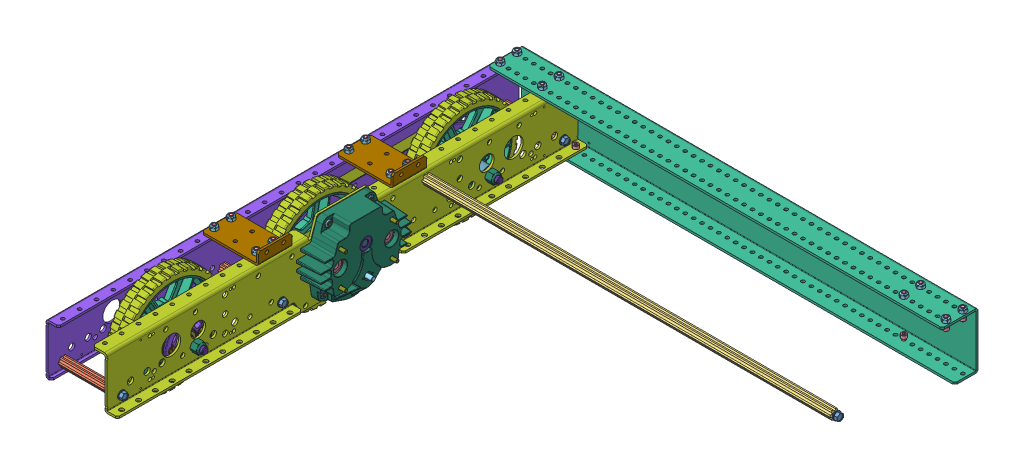
SolidWorks assembly AM14U3 Square Half, configuration Default. Lengths in mm.
Overall size (722.96 215.23 715.14).
150 component instances, 35 part files, 25 mates.
Components (placement in the parent):
- AM14U3 Square Frame Half-1: AM14U3 Square Frame Half [Default] at (326.068 37.2757 -291.2758) size (722.38 116.33 715.14)
  - 0.25-20 x 0.75 in Thread Rolling Screw-1: 0.25-20 x 0.75 in Thread Rolling Screw [FHTS 0.25-20-G-0.75-C] at (-600.075 -67.691 639.064) x (-1 0 0) z (0 0.924225 0.381849) size (24.64 12.19 12.19)
  - 0.25-20 x 0.75 in Thread Rolling Screw-4: 0.25-20 x 0.75 in Thread Rolling Screw [FHTS 0.25-20-G-0.75-C] at (-600.075 -67.691 -27.94) x (-1 0 0) z (0 0.924225 0.381849) size (24.64 12.19 12.19)
  - 0.25-20 x 0.75 in Thread Rolling Screw-5: 0.25-20 x 0.75 in Thread Rolling Screw [FHTS 0.25-20-G-0.75-C] at (-692.15 -67.691 -27.813) size (24.64 12.19 12.19)
  - 0.25-20 x 0.75 in Thread Rolling Screw-7: 0.25-20 x 0.75 in Thread Rolling Screw [FHTS 0.25-20-G-0.75-C] at (-603.25 -15.494 178.562) size (24.64 12.19 12.19)
  - 0.25-20 x 0.75 in Thread Rolling Screw-9: 0.25-20 x 0.75 in Thread Rolling Screw [FHTS 0.25-20-G-0.75-C] at (-692.15 -67.691 638.937) size (24.64 12.19 12.19)
  - 0.25-20 x 0.75 in Thread Rolling Screw-10: 0.25-20 x 0.75 in Thread Rolling Screw [FHTS 0.25-20-G-0.75-C] at (19.05 -15.494 178.562) x (-1 0 0) z (0 0.525103 -0.851039) size (24.64 12.19 12.19)
  - 500 Churro 3.375 in-1: 500 Churro 3.375 in [Default] at (-603.25 -67.691 -27.813) x (0 -0.866025 0.5) z (-1 0 0) size (14.66 12.7 85.72)
  - 500 Churro 3.375 in-2: 500 Churro 3.375 in [Default] at (-603.25 -67.691 638.937) x (0 -0.866025 0.5) z (-1 0 0) size (14.66 12.7 85.72)
  - 500 Churro 24.25 in-1: 500 Churro 24.25 in [Default] at (15.875 -15.494 178.562) x (0 0 -1) z (-1 0 0) size (14.66 12.7 615.95)
  - 10-32 x 0.5 in SHCS Screw-19: 10-32 x 0.5 in SHCS Screw [HX-SHCS 0.19-32x1.375x1-C] at (-679.45 -11.43 -11.938) x (0 1 0) z (0 0 1) size (17.53 7.94 7.94)
  - 10-32 x 0.5 in SHCS Screw-20: 10-32 x 0.5 in SHCS Screw [HX-SHCS 0.19-32x1.375x1-C] at (-679.45 -11.43 -37.338) x (0 1 0) z (0 0 1) size (17.53 7.94 7.94)
  - 10-32 x 0.5 in SHCS Screw-21: 10-32 x 0.5 in SHCS Screw [HX-SHCS 0.19-32x1.375x1-C] at (-615.95 -11.43 -37.338) x (0 1 0) z (0 0 1) size (17.53 7.94 7.94)
  - 10-32 x 0.5 in SHCS Screw-22: 10-32 x 0.5 in SHCS Screw [HX-SHCS 0.19-32x1.375x1-C] at (-615.95 -11.43 -11.938) x (0 1 0) z (0 0 1) size (17.53 7.94 7.94)
  - 10-32 x 0.5 in SHCS Screw-23: 10-32 x 0.5 in SHCS Screw [HX-SHCS 0.19-32x1.375x1-C] at (-590.55 -73.152 -37.338) x (0 -1 0) z (0 0 1) size (17.53 7.94 7.94)
  - 10-32 x 0.5 in SHCS Screw-24: 10-32 x 0.5 in SHCS Screw [HX-SHCS 0.19-32x1.375x1-C] at (-6.35 -11.176 -37.338) x (0 1 0) z (0.222581 0 0.974914) size (17.53 7.94 7.94)
  - 10-32 x 0.5 in SHCS Screw-25: 10-32 x 0.5 in SHCS Screw [HX-SHCS 0.19-32x1.375x1-C] at (-6.35 -11.176 -11.938) x (0 1 0) z (0.81526 0 0.579096) size (17.53 7.94 7.94)
  - 10-32 x 0.5 in SHCS Screw-26: 10-32 x 0.5 in SHCS Screw [HX-SHCS 0.19-32x1.375x1-C] at (-69.85 -11.176 -37.338) x (0 1 0) z (0 0 1) size (17.53 7.94 7.94)
  - 10-32 x 0.5 in SHCS Screw-27: 10-32 x 0.5 in SHCS Screw [HX-SHCS 0.19-32x1.375x1-C] at (-69.85 -11.176 -11.938) x (0 1 0) z (0.111454 0 0.99377) size (17.53 7.94 7.94)
  - 10-32 x 0.5 in SHCS Screw-28: 10-32 x 0.5 in SHCS Screw [HX-SHCS 0.19-32x1.375x1-C] at (-95.25 -73.406 -37.338) x (0 -1 0) z (0.007214 0 0.999974) size (17.53 7.94 7.94)
  - 10-32 Nylock Nut-19: 10-32 Nylock Nut [Default] at (-679.45 0 -11.938) x (1 0 0) z (0 1 0) size (10.18 11.01 7.1)
  - 10-32 Nylock Nut-21: 10-32 Nylock Nut [Default] at (-679.45 0 -37.338) x (1 0 0) z (0 1 0) size (10.18 11.01 7.1)
  - 10-32 Nylock Nut-22: 10-32 Nylock Nut [Default] at (-615.95 0 -11.938) x (1 0 0) z (0 1 0) size (10.18 11.01 7.1)
  - 10-32 Nylock Nut-23: 10-32 Nylock Nut [Default] at (-615.95 0 -37.338) x (1 0 0) z (0 1 0) size (10.18 11.01 7.1)
  - 10-32 Nylock Nut-25: 10-32 Nylock Nut [Default] at (-69.85 0 -11.938) x (1 0 0) z (0 1 0) size (10.18 11.01 7.1)
  - 10-32 Nylock Nut-26: 10-32 Nylock Nut [Default] at (-69.85 0 -37.338) x (1 0 0) z (0 1 0) size (10.18 11.01 7.1)
  - 10-32 Nylock Nut-27: 10-32 Nylock Nut [Default] at (-6.35 0 -11.938) x (1 0 0) z (0 1 0) size (10.18 11.01 7.1)
  - 10-32 Nylock Nut-28: 10-32 Nylock Nut [Default] at (-6.35 0 -37.338) x (1 0 0) z (0 1 0) size (10.18 11.01 7.1)
  - 10-32 Nylock Nut-29: 10-32 Nylock Nut [Default] at (-95.25 -84.582 -37.338) x (1 0 0) z (0 -1 0) size (10.18 11.01 7.1)
  - 10-32 Nylock Nut-30: 10-32 Nylock Nut [Default] at (-590.55 -84.582 -37.338) x (1 0 0) z (0 -1 0) size (10.18 11.01 7.1)
  - 10-32 x 0.5 in SHCS Screw-29: 10-32 x 0.5 in SHCS Screw [HX-SHCS 0.19-32x1.375x1-C] at (-679.45 -11.43 191.262) x (0 1 0) z (0 0 1) size (17.53 7.94 7.94)
  - 10-32 x 0.5 in SHCS Screw-30: 10-32 x 0.5 in SHCS Screw [HX-SHCS 0.19-32x1.375x1-C] at (-679.45 -11.43 216.662) x (0 1 0) z (0 0 1) size (17.53 7.94 7.94)
  - 10-32 x 0.5 in SHCS Screw-31: 10-32 x 0.5 in SHCS Screw [HX-SHCS 0.19-32x1.375x1-C] at (-615.95 -11.43 191.262) x (0 1 0) z (0 0 1) size (17.53 7.94 7.94)
  - 10-32 x 0.5 in SHCS Screw-32: 10-32 x 0.5 in SHCS Screw [HX-SHCS 0.19-32x1.375x1-C] at (-615.95 -11.43 216.662) x (0 1 0) z (0 0 1) size (17.53 7.94 7.94)
  - 10-32 x 0.5 in SHCS Screw-33: 10-32 x 0.5 in SHCS Screw [HX-SHCS 0.19-32x1.375x1-C] at (-615.95 -11.43 394.462) x (0 1 0) z (0 0 1) size (17.53 7.94 7.94)
  - 10-32 x 0.5 in SHCS Screw-34: 10-32 x 0.5 in SHCS Screw [HX-SHCS 0.19-32x1.375x1-C] at (-615.95 -11.43 419.862) x (0 1 0) z (0 0 1) size (17.53 7.94 7.94)
  - 10-32 x 0.5 in SHCS Screw-35: 10-32 x 0.5 in SHCS Screw [HX-SHCS 0.19-32x1.375x1-C] at (-679.45 -11.43 394.462) x (0 1 0) z (0 0 1) size (17.53 7.94 7.94)
  - 10-32 x 0.5 in SHCS Screw-36: 10-32 x 0.5 in SHCS Screw [HX-SHCS 0.19-32x1.375x1-C] at (-679.45 -11.43 419.862) x (0 1 0) z (0 0 1) size (17.53 7.94 7.94)
  - 10-32 Nylock Nut-31: 10-32 Nylock Nut [Default] at (-679.45 -0.254 419.862) x (1 0 0) z (0 1 0) size (10.18 11.01 7.1)
  - 10-32 Nylock Nut-32: 10-32 Nylock Nut [Default] at (-679.45 -0.254 394.462) x (1 0 0) z (0 1 0) size (10.18 11.01 7.1)
  - 10-32 Nylock Nut-33: 10-32 Nylock Nut [Default] at (-615.95 -0.254 394.462) x (1 0 0) z (0 1 0) size (10.18 11.01 7.1)
  - 10-32 Nylock Nut-34: 10-32 Nylock Nut [Default] at (-615.95 -0.254 419.862) x (1 0 0) z (0 1 0) size (10.18 11.01 7.1)
  - 10-32 Nylock Nut-35: 10-32 Nylock Nut [Default] at (-679.45 -0.254 216.662) x (1 0 0) z (0 1 0) size (10.18 11.01 7.1)
  - 10-32 Nylock Nut-37: 10-32 Nylock Nut [Default] at (-679.45 -0.254 191.262) x (1 0 0) z (0 1 0) size (10.18 11.01 7.1)
  - 10-32 Nylock Nut-38: 10-32 Nylock Nut [Default] at (-615.95 -0.254 216.662) x (1 0 0) z (0 1 0) size (10.18 11.01 7.1)
  - 10-32 Nylock Nut-39: 10-32 Nylock Nut [Default] at (-615.95 -0.254 191.262) x (1 0 0) z (0 1 0) size (10.18 11.01 7.1)
  - AM14U3 End Plate_Square-1: AM14U3 End Plate_Square [Default] at (-488.098 60.9785 -76.8664) x (1 0 0) z (0 -1 0) size (685.8 53.97 84.58)
  - AM14U3 Inner Plate_Square-1: AM14U3 Inner Plate_Square [Default] at (-612.1116 -19.2169 590.6409) x (0 0 -1) z (0 -1 0) size (711.2 38.1 116.33)
  - AM14U3 Outer Plate_Square-1: AM14U3 Outer Plate_Square [Default] at (-667.7485 -27.0221 21.6115) x (0 0 1) z (0 -1 0) size (711.2 19.05 77.72)
  - Bracket 2x3 Hole Pattern-1: Bracket 2x3 Hole Pattern [Default] at (-685.8 -3.429 445.262) size (85.72 19.05 50.8)
  - Bracket 2x3 Hole Pattern-2: Bracket 2x3 Hole Pattern [Default] at (-685.8 -3.429 242.062) size (85.72 19.05 50.8)
  - 500 Churro 3.375 in-5: 500 Churro 3.375 in [Default] at (-688.975 -66.929 397.637) x (0 0 -1) z (1 0 0) size (14.66 12.7 85.72)
  - 500 Churro 3.375 in-6: 500 Churro 3.375 in [Default] at (-688.975 -66.929 213.487) x (0 0 -1) z (1 0 0) size (14.66 12.7 85.72)
  - 0.25-20 x 0.75 in Thread Rolling Screw-11: 0.25-20 x 0.75 in Thread Rolling Screw [FHTS 0.25-20-G-0.75-C] at (-600.075 -66.929 397.637) x (-1 0 0) z (0 0.924225 0.381849) size (24.64 12.19 12.19)
  - 0.25-20 x 0.75 in Thread Rolling Screw-12: 0.25-20 x 0.75 in Thread Rolling Screw [FHTS 0.25-20-G-0.75-C] at (-600.075 -66.929 213.487) x (-1 0 0) z (0 0.924225 0.381849) size (24.64 12.19 12.19)
  - 0.25-20 x 0.75 in Thread Rolling Screw-13: 0.25-20 x 0.75 in Thread Rolling Screw [FHTS 0.25-20-G-0.75-C] at (-692.15 -66.929 397.637) size (24.64 12.19 12.19)
  - 0.25-20 x 0.75 in Thread Rolling Screw-14: 0.25-20 x 0.75 in Thread Rolling Screw [FHTS 0.25-20-G-0.75-C] at (-692.15 -66.929 213.487) size (24.64 12.19 12.19)
- Toughbox Mini Kit 1 - Yellow-1: Toughbox Mini Kit 1 - Yellow [Default] at (-324.5487 -32.7384 105.387) x (0 0.001296 0.999999) z (-1 0 0) size (140.05 131.97 142.29)
  - TB Mini Small Hex Shaft-1: TB Mini Small Hex Shaft [Default] at (-128.9299 31.4042 -52.3959) x (-0.63944 -0.768841 0) z (-0.768841 0.63944 0) size (11 38.23 9.52)
  - Large Cluster Gear Hex 50t 0.375 in-1: Large Cluster Gear Hex 50t 0.375 in [Default] at (-91.0349 50.9043 -67.5597) x (-0.63944 -0.768841 0) z (0 0 -1) size (65.97 66.04 10.16)
  - Bearing FR6ZZ-1: Bearing FR6ZZ [Default] at (-96.247 60.278 -52.5991) x (-0.893862 0.448342 0) z (0 0 1) size (24.69 24.69 7.16)
  - 10-32 Nylock Nut-1: 10-32 Nylock Nut [Default] at (-129.8464 -8.0737 -56.3837) x (0.501678 0.865055 0) z (0 0 -1) size (10.18 11.01 7.1)
  - 10-32 Nylock Nut-2: 10-32 Nylock Nut [Default] at (-59.2462 80.7349 -56.3837) x (0.999999 -0.001296 0) z (0 0 -1) size (10.18 11.01 7.1)
  - 10-32 Nylock Nut-3: 10-32 Nylock Nut [Default] at (-122.7461 80.8172 -56.3837) x (0.500567 0.865698 0) z (0 0 -1) size (10.18 11.01 7.1)
  - 10-32 Nylock Nut-4: 10-32 Nylock Nut [Default] at (-52.3764 -8.1741 -56.3837) x (-0.501678 -0.865055 0) z (0 0 -1) size (10.18 11.01 7.1)
  - Washer 5-16 in-1: Washer 5-16 in [Default] at (-52.3162 38.3079 -77.7705) x (-0.418041 0.908428 0) z (0 0 -1) size (17.53 17.53 1.47)
  - Washer 5-16 in-2: Washer 5-16 in [Default] at (-52.3162 38.3079 -76.2973) x (0.897267 -0.441488 0) z (0 0 -1) size (17.53 17.53 1.47)
  - Washer 5-16 in-3: Washer 5-16 in [Default] at (-129.7861 38.4083 -77.7705) x (-0.990116 0.140253 0) z (0 0 1) size (17.53 17.53 1.47)
  - Washer 5-16 in-4: Washer 5-16 in [Default] at (-129.7861 38.4083 -79.2437) x (-0.681761 0.731575 0) z (0 0 1) size (17.53 17.53 1.47)
  - CIM Gear 14t 8 mm-1: CIM Gear 14t 8 mm [Default] at (-52.3162 38.3079 -63.5973) x (0.081921 0.996639 0) z (0 0 -1) size (20.03 20.32 12.7)
  - CIM Gear 14t 8 mm-2: CIM Gear 14t 8 mm [Default] at (-129.7861 38.4083 -63.5973) x (0.725998 0.687697 0) z (0 0 -1) size (20.03 20.32 12.7)
  - TB Mini Housing-1: TB Mini Housing [Default] at (-91.0876 10.1882 -86.3557) x (0.999999 -0.001296 0) z (0 0 1) size (139.9 118.55 41.54)
  - 10-32 x 0.625 in SHCS Screw-1: 10-32 x 0.625 in SHCS Screw [Default] at (-52.2832 63.7078 -74.4685) x (-0.564778 -0.825243 0) z (-0.825243 0.564778 0) size (7.82 20.65 7.82)
  - 10-32 x 0.625 in SHCS Screw-2: 10-32 x 0.625 in SHCS Screw [Default] at (-122.7461 80.8172 -42.5915) x (0.507484 -0.861661 0) z (-0.861661 -0.507484 0) size (7.82 20.65 7.82)
  - 10-32 x 0.625 in SHCS Screw-3: 10-32 x 0.625 in SHCS Screw [Default] at (-52.3764 -8.1741 -42.5915) x (0.507484 -0.861661 0) z (-0.861661 -0.507484 0) size (7.82 20.65 7.82)
  - 10-32 x 0.625 in SHCS Screw-4: 10-32 x 0.625 in SHCS Screw [Default] at (-129.8464 -8.0737 -42.5915) x (0.507484 -0.861661 0) z (-0.861661 -0.507484 0) size (7.82 20.65 7.82)
  - 10-32 x 0.625 in SHCS Screw-5: 10-32 x 0.625 in SHCS Screw [Default] at (-59.2462 80.7349 -42.5915) x (0.740711 -0.671824 0) z (-0.671824 -0.740711 0) size (7.82 20.65 7.82)
  - 10-32 x 0.625 in SHCS Screw-6: 10-32 x 0.625 in SHCS Screw [Default] at (-52.3491 12.9079 -74.4685) x (-0.564778 -0.825243 0) z (-0.825243 0.564778 0) size (7.82 20.65 7.82)
  - 10-32 x 0.625 in SHCS Screw-7: 10-32 x 0.625 in SHCS Screw [Default] at (-129.7532 63.8083 -74.4685) x (-0.966277 -0.257503 0) z (-0.257503 0.966277 0) size (7.82 20.65 7.82)
  - 10-32 x 0.625 in SHCS Screw-8: 10-32 x 0.625 in SHCS Screw [Default] at (-129.819 13.0083 -74.4685) x (-0.99652 0.083357 0) z (0.083357 0.99652 0) size (7.82 20.65 7.82)
  - Bearing R6ZZ-3: Bearing R6ZZ [Default] at (-91.0349 50.9043 -84.8317) x (0.958138 -0.286306 0) z (0 0 1) size (22.23 22.23 7.11)
  - Bearing R6ZZ-4: Bearing R6ZZ [Default] at (-91.0876 10.1882 -84.8317) x (-0.661529 0.74992 0) z (0 0 1) size (22.23 22.23 7.11)
  - Retaining Clip 8 mm-1: Retaining Clip 8 mm [Default] at (-129.7861 38.4083 -63.5973) x (0 0 1) z (-1 0 0) size (1.09 14.83 14.83)
  - Retaining Clip 8 mm-2: Retaining Clip 8 mm [Default] at (-52.3162 38.3079 -63.5973) x (0 0 1) z (-1 0 0) size (1.09 14.83 14.83)
  - External Klipring 0.5 in-1: External Klipring 0.5 in [Default] at (-91.0876 10.1882 -64.4355) x (0.996411 -0.084651 0) z (0 0 1) size (19.07 20.96 1.27)
  - Hex Bearing FR8ZZ-1: Hex Bearing FR8ZZ [Default] at (-91.0876 10.1882 -44.6717) x (0.206517 -0.978443 0) z (0 0 -1) size (31.12 31.12 7.93)
  - Small Cluster Gear Hex 16t 0.375 in-1: Small Cluster Gear Hex 16t 0.375 in [Default] at (-91.0349 50.9043 -67.5597) x (0 0 1) z (0.346116 -0.938192 0) size (15.19 22.57 22.57)
  - Large Output Gear Hex 48t 0.5 in-1: Large Output Gear Hex 48t 0.5 in [Default] at (-91.0876 10.1882 -63.1655) x (0 0 1) z (0.744098 0.668071 0) size (10.21 63.42 63.42)
  - TB Mini Hex Output Shaft-2: TB Mini Hex Output Shaft [Default] at (-99.4862 -30.7356 -52.3197) x (0.206517 -0.978443 0) z (-0.978443 -0.206517 0) size (14.66 142.29 12.7)
- Wheel HiGrip 6 in - Hub, Double Pulley-1: Wheel HiGrip 6 in - Hub, Double Pulley [Default] at (-288.1818 8.7668 164.0924) x (-1 0 0) z (0 -0.669035 -0.743231) size (81.42 152.4 152.4)
  - Wheel HiGrip 6 in-1: Wheel HiGrip 6 in [Default] at (83.7987 67.439 110.9939) size (35.05 152.4 152.4)
    - Wheel HiGrip 6 in_Wheel-1: Wheel HiGrip 6 in_Wheel [Default] at (-52.6446 9.4231 21.378) size (35.05 132.08 132.08)
    - Wheel HiGrip 6 in_Tread-1: Wheel HiGrip 6 in_Tread [Default] at (-65.3446 9.4231 21.378) x (0 0 -1) z (1 0 0) size (152.4 152.4 25.58)
  - Half Pulley 42t 5 mm HTD-1: Half Pulley 42t 5 mm HTD [Default] at (47.6006 76.862 132.3719) x (1 0 0) z (0 -0.5 0.866025) size (13 74.23 74.23)
  - Half Pulley 42t 5 mm HTD-2: Half Pulley 42t 5 mm HTD [Default] at (64.263 76.862 132.3719) x (-1 0 0) z (0 -0.499927 0.866067) size (13 74.23 74.23)
  - 10-24 x 1.25 in Thread Forming Screw-1: 10-24 x 1.25 in Thread Forming Screw [93882A213] at (63.247 76.8605 108.5602) x (0 0 -1) z (1 0 0) size (10.52 10.52 35.59)
  - 10-24 x 1.25 in Thread Forming Screw-2: 10-24 x 1.25 in Thread Forming Screw [93882A213] at (63.247 97.4833 120.4656) x (0 0 -1) z (1 0 0) size (10.52 10.52 35.59)
  - 10-24 x 1.25 in Thread Forming Screw-3: 10-24 x 1.25 in Thread Forming Screw [93882A213] at (63.247 56.2398 144.2799) x (0 0 -1) z (1 0 0) size (10.52 10.52 35.59)
  - 10-24 x 1.25 in Thread Forming Screw-4: 10-24 x 1.25 in Thread Forming Screw [93882A213] at (63.247 76.8625 156.1852) x (0 -0.95788 -0.287168) z (1 0 0) size (10.52 10.52 35.59)
  - 10-24 x 1.25 in Thread Forming Screw-5: 10-24 x 1.25 in Thread Forming Screw [93882A213] at (63.247 97.4843 144.2781) x (0 -0.868976 0.494854) z (1 0 0) size (10.52 10.52 35.59)
  - 10-24 x 1.25 in Thread Forming Screw-6: 10-24 x 1.25 in Thread Forming Screw [93882A213] at (63.247 56.2388 120.4674) x (0 -0.748729 -0.662876) z (1 0 0) size (10.52 10.52 35.59)
  - Half Pulley 42t 5 mm HTD-3: Half Pulley 42t 5 mm HTD [Default] at (-1.9548 76.8628 132.3714) x (1 0 0) z (0 -1 -0.000063) size (13 74.23 74.23)
  - Half Pulley 42t 5 mm HTD-4: Half Pulley 42t 5 mm HTD [Default] at (14.7076 76.8628 132.3714) x (-1 0 0) z (0 -1 0.000021) size (13 74.23 74.23)
  - Hex Hub 500 EX-1: Hex Hub 500 EX [Default] at (-8.3048 76.8628 132.3714) x (0 -0.866025 -0.5) z (0 -0.5 0.866025) size (55.37 25.4 51.33)
  - 10-24 x 1.25 in Thread Forming Screw-7: 10-24 x 1.25 in Thread Forming Screw [93882A213] at (-5.2568 97.485 120.4652) x (0 0 1) z (-1 0 0) size (10.52 10.52 35.59)
  - 10-24 x 1.25 in Thread Forming Screw-8: 10-24 x 1.25 in Thread Forming Screw [93882A213] at (-5.2568 76.8628 108.5589) x (0 0 1) z (-1 0 0) size (10.52 10.52 35.59)
  - 10-24 x 1.25 in Thread Forming Screw-9: 10-24 x 1.25 in Thread Forming Screw [93882A213] at (-5.2568 56.2406 120.4652) x (0 0 1) z (-1 0 0) size (10.52 10.52 35.59)
  - 10-24 x 1.25 in Thread Forming Screw-10: 10-24 x 1.25 in Thread Forming Screw [93882A213] at (-5.2568 97.485 144.2777) x (0 -0.99374 -0.111715) z (-1 0 0) size (10.52 10.52 35.59)
  - 10-24 x 1.25 in Thread Forming Screw-11: 10-24 x 1.25 in Thread Forming Screw [93882A213] at (-5.2568 56.2406 144.2777) x (0 -0.138911 0.990305) z (-1 0 0) size (10.52 10.52 35.59)
  - 10-24 x 1.25 in Thread Forming Screw-12: 10-24 x 1.25 in Thread Forming Screw [93882A213] at (-5.2568 76.8628 156.1839) x (0 -0.98811 -0.15375) z (-1 0 0) size (10.52 10.52 35.59)
  - Hex Spacer 0.57 in x 0.5 ID-1: Hex Spacer 0.57 in x 0.5 ID [Default] at (57.8495 76.862 132.3719) x (0 -0.866025 -0.5) z (0 -0.5 0.866025) size (28.55 14.48 28.55)
- Wheel HiGrip 6 in - Bearings, Pulleys, Spacers-1: Wheel HiGrip 6 in - Bearings, Pulleys, Spacers [Default] at (-351.6685 -97.7524 104.462) size (85.56 152.4 152.4)
  - Wheel HiGrip 6 in-1: Wheel HiGrip 6 in [Default] at (83.7987 67.439 110.9939) size (35.05 152.4 152.4)
    - Wheel HiGrip 6 in_Wheel-1: Wheel HiGrip 6 in_Wheel [Default] at (-52.6446 9.4231 21.378) size (35.05 132.08 132.08)
    - Wheel HiGrip 6 in_Tread-1: Wheel HiGrip 6 in_Tread [Default] at (-65.3446 9.4231 21.378) x (0 0 -1) z (1 0 0) size (152.4 152.4 25.58)
  - Half Pulley 42t 5 mm HTD-1: Half Pulley 42t 5 mm HTD [Default] at (47.6006 76.862 132.3719) x (1 0 0) z (0 -0.5 0.866025) size (13 74.23 74.23)
  - Half Pulley 42t 5 mm HTD-2: Half Pulley 42t 5 mm HTD [Default] at (64.263 76.862 132.3719) x (-1 0 0) z (0 -0.499927 0.866067) size (13 74.23 74.23)
  - Bearing 1614ZZ-1: Bearing 1614ZZ [Default] at (62.612 76.862 132.3719) x (0 -0.157148 -0.987575) z (-1 0 0) size (28.57 28.57 9.53)
  - Bearing 1614ZZ-2: Bearing 1614ZZ [Default] at (15.2791 76.862 132.3719) x (0 0 -1) z (1 0 0) size (28.57 28.57 9.53)
  - 10-24 x 1.25 in Thread Forming Screw-1: 10-24 x 1.25 in Thread Forming Screw [93882A213] at (63.247 76.8605 108.5602) x (0 0 -1) z (1 0 0) size (10.52 10.52 35.59)
  - 10-24 x 1.25 in Thread Forming Screw-2: 10-24 x 1.25 in Thread Forming Screw [93882A213] at (63.247 97.4833 120.4656) x (0 0 -1) z (1 0 0) size (10.52 10.52 35.59)
  - 10-24 x 1.25 in Thread Forming Screw-3: 10-24 x 1.25 in Thread Forming Screw [93882A213] at (63.247 56.2398 144.2799) x (0 0 -1) z (1 0 0) size (10.52 10.52 35.59)
  - 10-24 x 1.25 in Thread Forming Screw-4: 10-24 x 1.25 in Thread Forming Screw [93882A213] at (63.247 76.8625 156.1852) x (0 -0.95788 -0.287168) z (1 0 0) size (10.52 10.52 35.59)
  - 10-24 x 1.25 in Thread Forming Screw-5: 10-24 x 1.25 in Thread Forming Screw [93882A213] at (63.247 97.4843 144.2781) x (0 -0.868976 0.494854) z (1 0 0) size (10.52 10.52 35.59)
  - 10-24 x 1.25 in Thread Forming Screw-6: 10-24 x 1.25 in Thread Forming Screw [93882A213] at (63.247 56.2388 120.4674) x (0 -0.977348 -0.211637) z (1 0 0) size (10.52 10.52 35.59)
  - Spacer 0.28 in x 0.382 ID-1: Spacer 0.28 in x 0.382 ID [Default] at (74.4865 76.862 132.3719) x (0 -0.35357 0.935408) z (-1 0 0) size (13.16 13.16 7.11)
  - Spacer 0.85 in x 0.38 ID-1: Spacer 0.85 in x 0.38 ID [Default] at (-11.0734 76.862 132.3719) x (0 0 -1) z (1 0 0) size (19.05 19.05 21.59)
- Wheel HiGrip 6 in - Bearings, Pulleys, Spacers-2: Wheel HiGrip 6 in - Bearings, Pulleys, Spacers [Default] at (-288.2554 72.1013 -86.6776) x (-1 0 0) z (0 -0.924225 -0.381849) size (85.56 152.4 152.4)
  - Wheel HiGrip 6 in-1: Wheel HiGrip 6 in [Default] at (83.7987 67.439 110.9939) size (35.05 152.4 152.4)
    - Wheel HiGrip 6 in_Wheel-1: Wheel HiGrip 6 in_Wheel [Default] at (-52.6446 9.4231 21.378) size (35.05 132.08 132.08)
    - Wheel HiGrip 6 in_Tread-1: Wheel HiGrip 6 in_Tread [Default] at (-65.3446 9.4231 21.378) x (0 0 -1) z (1 0 0) size (152.4 152.4 25.58)
  - Half Pulley 42t 5 mm HTD-1: Half Pulley 42t 5 mm HTD [Default] at (47.6006 76.862 132.3719) x (1 0 0) z (0 -0.5 0.866025) size (13 74.23 74.23)
  - Half Pulley 42t 5 mm HTD-2: Half Pulley 42t 5 mm HTD [Default] at (64.263 76.862 132.3719) x (-1 0 0) z (0 -0.499927 0.866067) size (13 74.23 74.23)
  - Bearing 1614ZZ-1: Bearing 1614ZZ [Default] at (62.612 76.862 132.3719) x (0 -0.157148 -0.987575) z (-1 0 0) size (28.57 28.57 9.53)
  - Bearing 1614ZZ-2: Bearing 1614ZZ [Default] at (15.2791 76.862 132.3719) x (0 0 -1) z (1 0 0) size (28.57 28.57 9.53)
  - 10-24 x 1.25 in Thread Forming Screw-1: 10-24 x 1.25 in Thread Forming Screw [93882A213] at (63.247 76.8605 108.5602) x (0 0 -1) z (1 0 0) size (10.52 10.52 35.59)
  - 10-24 x 1.25 in Thread Forming Screw-2: 10-24 x 1.25 in Thread Forming Screw [93882A213] at (63.247 97.4833 120.4656) x (0 0 -1) z (1 0 0) size (10.52 10.52 35.59)
  - 10-24 x 1.25 in Thread Forming Screw-3: 10-24 x 1.25 in Thread Forming Screw [93882A213] at (63.247 56.2398 144.2799) x (0 0 -1) z (1 0 0) size (10.52 10.52 35.59)
  - 10-24 x 1.25 in Thread Forming Screw-4: 10-24 x 1.25 in Thread Forming Screw [93882A213] at (63.247 76.8625 156.1852) x (0 -0.95788 -0.287168) z (1 0 0) size (10.52 10.52 35.59)
  - 10-24 x 1.25 in Thread Forming Screw-5: 10-24 x 1.25 in Thread Forming Screw [93882A213] at (63.247 97.4843 144.2781) x (0 -0.868976 0.494854) z (1 0 0) size (10.52 10.52 35.59)
  - 10-24 x 1.25 in Thread Forming Screw-6: 10-24 x 1.25 in Thread Forming Screw [93882A213] at (63.247 56.2388 120.4674) x (0 -0.977348 -0.211637) z (1 0 0) size (10.52 10.52 35.59)
  - Spacer 0.28 in x 0.382 ID-1: Spacer 0.28 in x 0.382 ID [Default] at (74.4865 76.862 132.3719) x (0 -0.35357 0.935408) z (-1 0 0) size (13.16 13.16 7.11)
  - Spacer 0.85 in x 0.38 ID-1: Spacer 0.85 in x 0.38 ID [Default] at (-11.0734 76.862 132.3719) x (0 0 -1) z (1 0 0) size (19.05 19.05 21.59)
- Hex Bearing FR8ZZ-1: Hex Bearing FR8ZZ [Default] at (-369.3104 -22.6683 14.2862) x (0 0.309139 -0.951017) z (1 0 0) size (31.12 31.12 7.93)
- 0.375-16 Nylock Nut-1: 0.375-16 Nylock Nut [91831A127] at (-274.007 -20.8903 236.8339) x (0 -1 0) z (0 0 1) size (14.29 12 16.5)
- 0.375-16 Nylock Nut-2: 0.375-16 Nylock Nut [91831A127] at (-274.007 -20.8903 -208.2615) x (0 -1 0) z (0 0 1) size (14.29 12 16.5)
- Timing Belt HTD 15 mm_Square-1: Timing Belt HTD 15 mm_Square [Default] at (-289.0679 -20.8903 236.8339) x (0 -0.007989 -0.999968) z (-1 0 0) size (291.74 69.19 15)
- Timing Belt HTD 15 mm_Square-2: Timing Belt HTD 15 mm_Square [Default] at (-335.856 -20.8903 -208.2615) x (0 -0.007989 0.999968) z (-1 0 0) size (291.74 69.19 15)
- 0.375-16 x 4.25 in HHS Bolt-3: 0.375-16 x 4.25 in HHS Bolt [HFBOLT 0.375-16x2.5x1-C] at (-372.2542 -20.8903 236.8339) size (114.12 16.48 14.27)
- 0.375-16 x 4.25 in HHS Bolt-4: 0.375-16 x 4.25 in HHS Bolt [HFBOLT 0.375-16x2.5x1-C] at (-372.2542 -20.8903 -208.2615) size (114.12 16.48 14.27)
Mates (geometry in assembly coordinates):
- Concentric1: concentric anti-aligned: cylinder of AM14U3 Square Frame Half-1/AM14U3 Inner Plate_Square-1 through (-277.182 -22.6683 14.2862) axis (1 0 0) radius 14.2875; cylinder of Toughbox Mini Kit 1 - Yellow-1/Hex Bearing FR8ZZ-1 through (-271.9496 -22.6683 14.2862) axis (-1 0 0) radius 14.2875
- Parallel1: parallel: plane of AM14U3 Square Frame Half-1/AM14U3 Inner Plate_Square-1 through (-274.007 57.3417 -33.3388) normal (0 1 0); line of Toughbox Mini Kit 1 - Yellow-1/TB Mini Housing-1 through (-273.4813 56.8989 -17.4638) axis (0 0 1)
- Coincident2: coincident anti-aligned: plane of AM14U3 Square Frame Half-1/AM14U3 Inner Plate_Square-1 through (-274.007 29.9097 420.6862) normal (1 0 0); plane of Toughbox Mini Kit 1 - Yellow-1/TB Mini Housing-1 through (-274.007 -22.6683 14.2862) normal (-1 0 0)
- Concentric2: concentric anti-aligned: cylinder of AM14U3 Square Frame Half-1/AM14U3 Outer Plate_Square-1 through (-254.956 -20.8903 236.8339) axis (-1 0 0) radius 4.826; cylinder of Wheel HiGrip 6 in - Bearings, Pulleys, Spacers-1/Spacer 0.28 in x 0.382 ID-1 through (-284.294 -20.8903 236.8339) axis (1 0 0) radius 6.5786
- Coincident3: coincident anti-aligned: plane of AM14U3 Square Frame Half-1/AM14U3 Inner Plate_Square-1 through (-277.182 29.9097 420.6862) normal (-1 0 0); plane of Wheel HiGrip 6 in - Bearings, Pulleys, Spacers-1/Spacer 0.28 in x 0.382 ID-1 through (-277.182 -20.8903 236.8339) normal (1 0 0)
- Concentric3: concentric anti-aligned: cylinder of AM14U3 Square Frame Half-1/AM14U3 Inner Plate_Square-1 through (-296.232 -20.8903 -208.2615) axis (1 0 0) radius 4.826; cylinder of Wheel HiGrip 6 in - Bearings, Pulleys, Spacers-2/Spacer 0.28 in x 0.382 ID-1 through (-355.6299 -20.8903 -208.2615) axis (-1 0 0) radius 6.5786
- Coincident4: coincident anti-aligned: plane of AM14U3 Square Frame Half-1/AM14U3 Inner Plate_Square-1 through (-277.182 29.9097 420.6862) normal (-1 0 0); plane of Wheel HiGrip 6 in - Bearings, Pulleys, Spacers-2/Spacer 0.85 in x 0.38 ID-1 through (-277.182 -20.8903 -208.2615) normal (1 0 0)
- Concentric4: concentric anti-aligned: cylinder of Toughbox Mini Kit 1 - Yellow-1/Hex Bearing FR8ZZ-1 through (-271.9496 -22.6683 14.2862) axis (-1 0 0) radius 14.2875; cylinder of Wheel HiGrip 6 in - Hub, Double Pulley-1/Hex Spacer 0.57 in x 0.5 ID-1 through (-360.5093 -22.6683 14.2862) axis (1 0 0) radius 14.2748
- Parallel2: parallel anti-aligned: plane of Toughbox Mini Kit 1 - Yellow-1/TB Mini Hex Output Shaft-2 through (-246.829 -15.496 12.7626) normal (0 0.743231 -0.669035); plane of Wheel HiGrip 6 in - Hub, Double Pulley-1/Hex Hub 500 EX-1 through (-279.877 -15.4808 12.7594) normal (0 -0.743231 0.669035)
- Coincident6: coincident anti-aligned: plane of Toughbox Mini Kit 1 - Yellow-1/Hex Bearing FR8ZZ-1 through (-279.877 -22.6683 14.2862) normal (-1 0 0); plane of Wheel HiGrip 6 in - Hub, Double Pulley-1/Hex Hub 500 EX-1 through (-279.877 -22.6675 14.286) normal (1 0 0)
- Concentric51: concentric aligned: cylinder of AM14U3 Square Frame Half-1/AM14U3 Outer Plate_Square-1 through (-362.907 -22.6683 14.2862) axis (-1 0 0) radius 14.2875; cylinder of Hex Bearing FR8ZZ-1 through (-361.383 -22.6683 14.2862) axis (-1 0 0) radius 13.97
- Coincident71: coincident anti-aligned: plane of AM14U3 Square Frame Half-1/AM14U3 Outer Plate_Square-1 through (-362.907 29.9097 -392.1138) normal (1 0 0); plane of Hex Bearing FR8ZZ-1 through (-362.907 -18.3497 1.0005) normal (-1 0 0)
- Coincident8: coincident anti-aligned: plane of Toughbox Mini Kit 1 - Yellow-1/TB Mini Hex Output Shaft-2 through (-246.829 -15.496 12.7626) normal (0 0.743231 -0.669035); plane of Hex Bearing FR8ZZ-1 through (-361.383 -15.496 12.7626) normal (0 -0.743231 0.669035)
- Coincident11: coincident anti-aligned: plane of AM14U3 Square Frame Half-1/AM14U3 Inner Plate_Square-1 through (-274.007 29.9097 420.6862) normal (1 0 0); plane of 0.375-16 Nylock Nut-1 through (-274.007 -13.7466 224.4605) normal (-1 0 0)
- Coincident12: coincident anti-aligned: plane of AM14U3 Square Frame Half-1/AM14U3 Inner Plate_Square-1 through (-274.007 29.9097 420.6862) normal (1 0 0); plane of 0.375-16 Nylock Nut-2 through (-274.007 -13.7466 -220.6349) normal (-1 0 0)
- Concentric11: concentric anti-aligned: cylinder of Wheel HiGrip 6 in - Bearings, Pulleys, Spacers-1/Spacer 0.85 in x 0.38 ID-1 through (-341.1519 -20.8903 236.8339) axis (-1 0 0) radius 9.525; cylinder of Timing Belt HTD 15 mm_Square-1 through (-304.0679 -20.8903 236.8339) axis (1 0 0) radius 33.4264
- Concentric12: concentric anti-aligned: cylinder of Hex Bearing FR8ZZ-1 through (-361.383 -22.6683 14.2862) axis (-1 0 0) radius 14.2875; cylinder of Timing Belt HTD 15 mm_Square-1 through (-304.0679 -22.6683 14.2862) axis (1 0 0) radius 33.4264
- Coincident13: coincident anti-aligned: plane of Wheel HiGrip 6 in - Bearings, Pulleys, Spacers-1/Half Pulley 42t 5 mm HTD-1 through (-304.0679 -20.8903 236.8339) normal (1 0 0); plane of Timing Belt HTD 15 mm_Square-1 through (-304.0679 -20.8903 236.8339) normal (-1 0 0)
- Concentric13: concentric anti-aligned: cylinder of Hex Bearing FR8ZZ-1 through (-361.383 -22.6683 14.2862) axis (-1 0 0) radius 14.2875; cylinder of Timing Belt HTD 15 mm_Square-2 through (-350.856 -22.6683 14.2862) axis (1 0 0) radius 33.4264
- Concentric14: concentric aligned: cylinder of Wheel HiGrip 6 in - Bearings, Pulleys, Spacers-2/Spacer 0.85 in x 0.38 ID-1 through (-298.772 -20.8903 -208.2615) axis (1 0 0) radius 9.525; cylinder of Timing Belt HTD 15 mm_Square-2 through (-350.856 -20.8903 -208.2615) axis (1 0 0) radius 33.4264
- Coincident14: coincident anti-aligned: plane of Wheel HiGrip 6 in - Bearings, Pulleys, Spacers-2/Half Pulley 42t 5 mm HTD-1 through (-335.856 -20.8903 -208.2615) normal (-1 0 0); plane of Timing Belt HTD 15 mm_Square-2 through (-335.856 -20.8903 -208.2615) normal (1 0 0)
- Concentric72: concentric aligned: cylinder of AM14U3 Square Frame Half-1/AM14U3 Outer Plate_Square-1 through (-254.956 -20.8903 236.8339) axis (-1 0 0) radius 4.826; cylinder of 0.375-16 x 4.25 in HHS Bolt-3 through (-372.2542 -20.8903 236.8339) axis (-1 0 0) radius 4.7625
- Coincident102: coincident anti-aligned: plane of AM14U3 Square Frame Half-1/AM14U3 Outer Plate_Square-1 through (-366.082 29.9097 -392.1138) normal (-1 0 0); plane of 0.375-16 x 4.25 in HHS Bolt-3 through (-366.082 -12.6488 236.8339) normal (1 0 0)
- Concentric731: concentric aligned: cylinder of AM14U3 Square Frame Half-1/AM14U3 Outer Plate_Square-1 through (-254.956 -20.8903 -208.2615) axis (-1 0 0) radius 4.826; cylinder of 0.375-16 x 4.25 in HHS Bolt-4 through (-372.2542 -20.8903 -208.2615) axis (-1 0 0) radius 7.1374
- Coincident1031: coincident anti-aligned: plane of AM14U3 Square Frame Half-1/AM14U3 Outer Plate_Square-1 through (-366.082 29.9097 -392.1138) normal (-1 0 0); plane of 0.375-16 x 4.25 in HHS Bolt-4 through (-366.082 -12.6488 -208.2615) normal (1 0 0)
